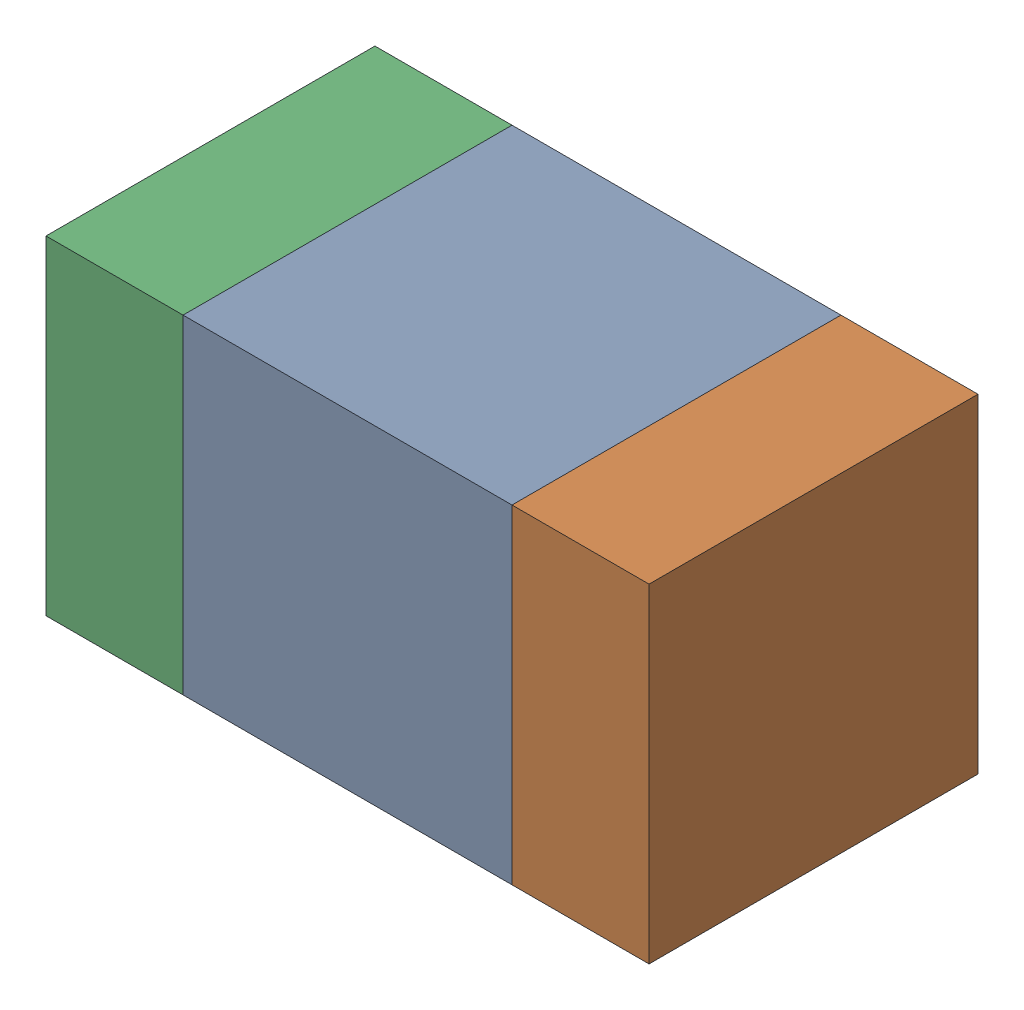
SolidWorks assembly C500_1PCB, configuration Default. Lengths in mm.
Overall size (1.1 0.6 0.6).
6 component instances, 2 part files, 0 mates.
Components (placement in the parent):
- 761606048-1: 761606048 [Default] at (156.6 118.8 0) size (0.6 0.6 0.6)
  - Extruded_9-1: Extruded_9 [Default] at origin size (0.6 0.6 0.6)
- 854785160-1: 854785160 [Default] at (157.025 118.8 0) size (0.25 0.6 0.6)
  - Extruded_19-1: Extruded_19 [Default] at origin size (0.25 0.6 0.6)
- 854785160-2: 854785160 [Default] at (156.175 118.8 0) size (0.25 0.6 0.6)
  - Extruded_19-1: Extruded_19 [Default] at origin size (0.25 0.6 0.6)
